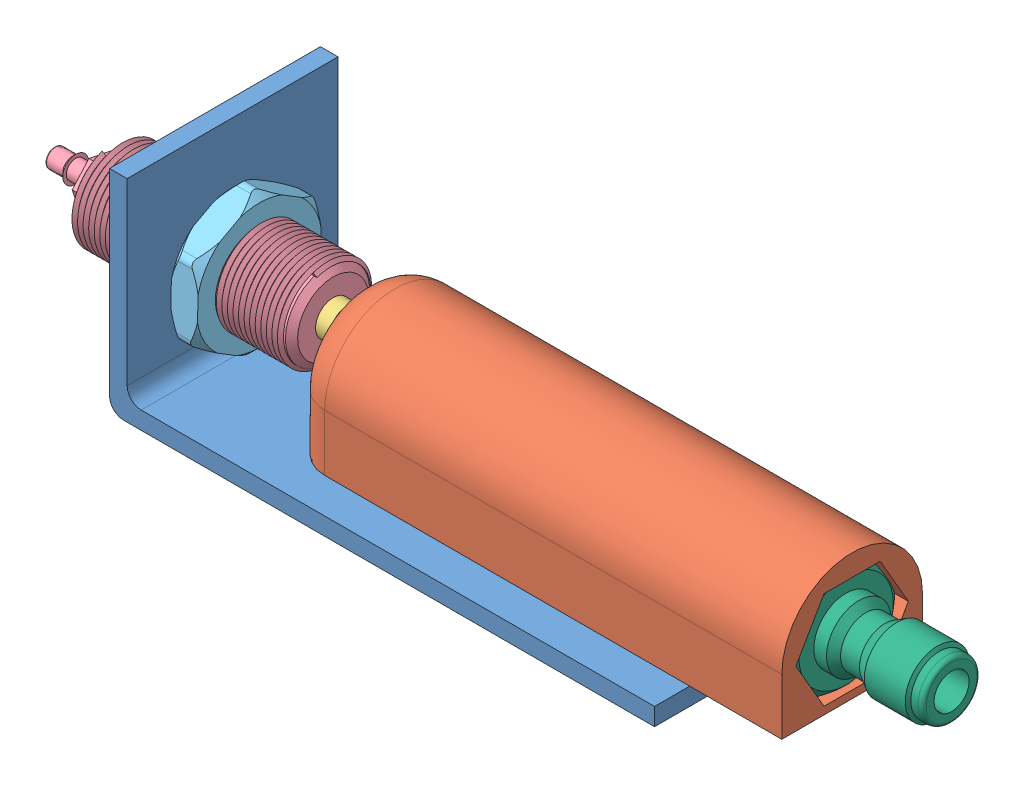
SolidWorks assembly QD assembly, configuration Default. Lengths in mm.
Overall size (161.98 50.98 38.1).
8 component instances, 7 part files, 18 mates.
Components (placement in the parent):
- Plate-1: Plate [Default] at (41.9272 42.6717 74.9889) size (98.42 38.1 38.1)
- Cover-1: Cover [Default] at (106.1892 56.0067 74.9889) x (0 0 -1) z (1 0 0) size (25.4 22.86 89.05)
- Piston-1: Piston [Default] at (-3.0308 58.5467 74.9889) x (0 -0.964067 -0.265658) z (1 0 0) size (13.33 13.33 30.91)
- Piston Outer-1: Piston Outer [Default] at (-27.2878 58.5467 74.9889) x (0 0.949125 0.314901) z (1 0 0) size (16.52 16.52 50.29)
- Nut-1: Nut [Default] at (-8.8728 58.5467 74.9889) x (0 0.498337 -0.866984) z (-1 0 0) size (25.19 22.23 5.78)
- Nut-2: Nut [Default] at (-0.8718 58.5467 74.9889) x (0 -0.999643 0.026719) z (-1 0 0) size (25.19 22.23 5.78)
- NPT-QD Fitting-1: NPT-QD Fitting [Default] at (105.097 55.979 74.9889) x (0 -0.866025 0.5) z (-1 0 0) size (21.89 17.4 37.31)
- AN-NPT -6 elbow-1: AN-NPT -6 elbow [5482K211] at (67.9622 55.979 74.9889) x (0 1 0) z (0 0 -1) size (33.41 34.63 14.44)
Mates (geometry in assembly coordinates):
- Concentric2: concentric anti-aligned: cylinder of Piston-1 through (24.9092 58.5467 74.9889) axis (-1 0 0) radius 3.175; cylinder of Piston Outer-1 through (-12.9368 58.5467 74.9889) axis (1 0 0) radius 3.175
- Concentric4: concentric anti-aligned: cylinder of Piston Outer-1 through (12.4632 58.5467 74.9889) axis (-1 0 0) radius 7.62; cylinder of Nut-2 through (-5.6978 58.5467 74.9889) axis (1 0 0) radius 7.9375
- Concentric5: concentric anti-aligned: cylinder of Piston Outer-1 through (12.4632 58.5467 74.9889) axis (-1 0 0) radius 7.62; cylinder of Nut-1 through (-13.6988 58.5467 74.9889) axis (1 0 0) radius 7.9375
- Coincident2: coincident anti-aligned: plane of Plate-1 through (-8.8728 42.6717 74.9889) normal (-1 0 0); plane of Nut-1 through (-8.8728 58.5467 74.9889) normal (1 0 0)
- Coincident3: coincident anti-aligned: plane of Plate-1 through (-5.6978 42.6717 74.9889) normal (1 0 0); plane of Nut-2 through (-5.6978 58.5467 74.9889) normal (-1 0 0)
- Distance1: distance = 18.415 mm aligned: plane of Piston Outer-1 through (-27.2878 58.5467 74.9889) normal (-1 0 0); plane of Plate-1 through (-8.8728 42.6717 74.9889) normal (-1 0 0)
- Coincident6: coincident anti-aligned: plane of Cover-1 through (24.9092 58.5467 74.9889) normal (-1 0 0); plane of Piston-1 through (24.9092 58.5467 74.9889) normal (1 0 0)
- Concentric6: concentric anti-aligned: cylinder of Cover-1 through (24.9092 58.5467 74.9889) axis (-1 0 0) radius 2.794; cylinder of Piston-1 through (15.0032 58.5467 74.9889) axis (1 0 0) radius 2.54
- Coincident5: coincident anti-aligned: plane of Plate-1 through (41.9272 45.8467 74.9889) normal (0 1 0); plane of Cover-1 through (17.2892 45.8467 87.6889) normal (0 -1 0)
- Concentric8: concentric anti-aligned: cylinder of Plate-1 through (-8.8728 58.5467 74.9889) axis (1 0 0) radius 8.001; cylinder of Piston Outer-1 through (12.4632 58.5467 74.9889) axis (-1 0 0) radius 7.62
- Distance6: distance = 0.127 mm anti-aligned: plane of Cover-1 through (75.7092 64.8055 69.9089) normal (0 -1 0); plane of NPT-QD Fitting-1 through (87.317 64.6785 80.0116) normal (0 1 0)
- Distance3: distance = 7.62 mm anti-aligned: plane of NPT-QD Fitting-1 through (87.317 55.979 74.9889) normal (-1 0 0); plane of AN-NPT -6 elbow-1 through (94.937 55.979 74.9889) normal (1 0 0)
- Concentric9: concentric anti-aligned: cylinder of NPT-QD Fitting-1 through (103.827 55.979 74.9889) axis (-1 0 0) radius 7.112; cylinder of AN-NPT -6 elbow-1 through (81.4496 55.979 74.9889) axis (1 0 0) radius 4.5917
- Parallel6: parallel anti-aligned: cylinder of Plate-1 through (67.9622 80.7717 74.9889) axis (0 -1 0) radius 7.3025; cylinder of AN-NPT -6 elbow-1 through (67.9622 29.7916 74.9889) axis (0 1 0) radius 4.7314
- Concentric12: concentric aligned: cylinder of Plate-1 through (67.9622 80.7717 74.9889) axis (0 -1 0) radius 7.3025; cylinder of AN-NPT -6 elbow-1 through (67.9622 55.979 74.9889) axis (0 -1 0) radius 7.1374
- Parallel7: parallel aligned: plane of Cover-1 through (106.1892 56.0067 74.9889) normal (1 0 0); plane of NPT-QD Fitting-1 through (105.097 55.979 74.9889) normal (1 0 0)
- Distance4: distance = 2.54 mm aligned: plane of Piston-1 through (15.0032 58.5467 74.9889) normal (1 0 0); plane of Piston Outer-1 through (12.4632 58.5467 74.9889) normal (1 0 0)
- Distance5: distance = 15.24 mm aligned: plane of Piston Outer-1 through (12.4632 58.5467 74.9889) normal (1 0 0); plane of Piston-1 through (27.7032 58.5467 74.9889) normal (1 0 0)
